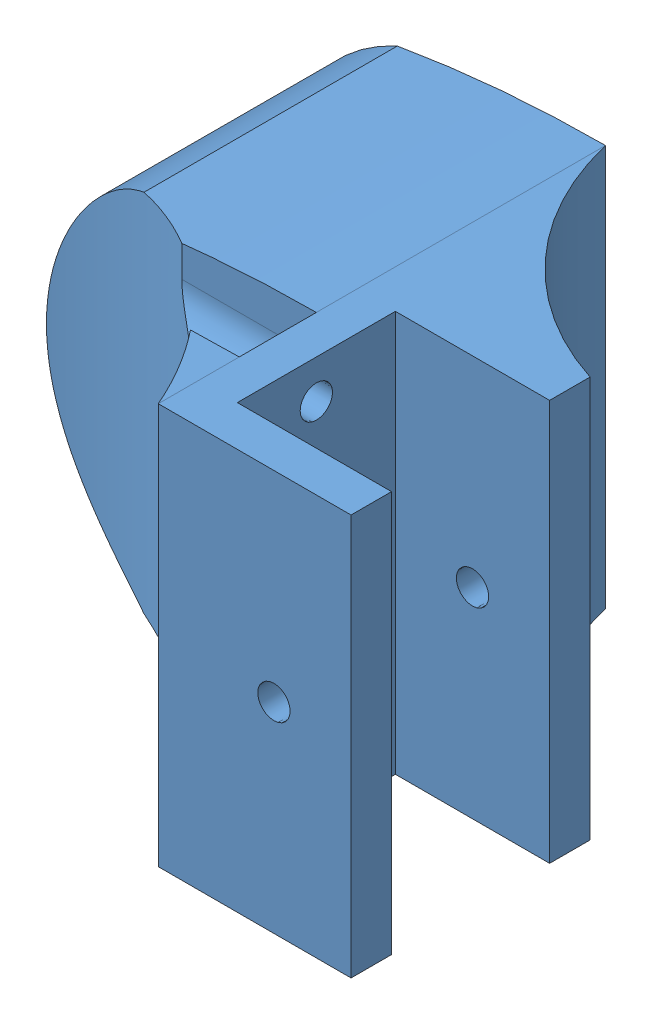
SolidWorks assembly Ролик с креплением зеркально, configuration По умолчанию. Lengths in mm.
Overall size (93.13 52 97.57).
3 component instances, 3 part files, 9 mates.
Components (placement in the parent):
- Крепление ролика зеркально-1: Крепление ролика зеркально [По умолчанию] at (0 26 -15.5) size (93.13 52 92.27)
- Шпилька-1: Шпилька [По умолчанию] at (-41.25 26 -47.8005) size (5 5 40)
- Ролик-1: Ролик [По умолчанию] at (-41.25 26 -32.05) x (1 0 0) z (0 -1 0) size (18 9 18)
Mates (geometry in assembly coordinates):
- Совпадение1: coincident anti-aligned: plane of Крепление ролика зеркально-1 through (0 0 15.5) normal (0 -1 0); plane of assembly through (0 0 0) normal (0 1 0)
- Совпадение2: coincident aligned: plane of Крепление ролика зеркально-1 through (0 26 0) normal (0 0 1); plane of assembly through (0 0 0) normal (0 0 1)
- Совпадение3: coincident aligned: plane of Крепление ролика зеркально-1 through (0 52 15.5) normal (1 0 0); plane of assembly through (0 0 0) normal (1 0 0)
- Концентричный1: concentric anti-aligned: cylinder of Крепление ролика зеркально-1 through (-41.25 26 -42.5) axis (0 0 1) radius 2.5; cylinder of Шпилька-1 through (-41.25 26 -7.8005) axis (0 0 -1) radius 2.5
- Параллельность1: parallel aligned: plane of Крепление ролика зеркально-1 through (0 52 15.5) normal (0 1 0); plane of Шпилька-1 through (-41.25 26 -47.8005) normal (0 1 0)
- Концентричный2: concentric anti-aligned: cylinder of Шпилька-1 through (-41.25 26 -7.8005) axis (0 0 -1) radius 2.5; cylinder of Ролик-1 through (-41.25 26 -23.05) axis (0 0 1) radius 2.5
- Совпадение5: coincident: line of Крепление ролика зеркально-1 through (35.2 52 -31.25) axis (1 0 0); plane of Ролик-1 through (-50.25 26 -31.25) normal (0 0 1)
- Параллельность2: parallel aligned: plane of Крепление ролика зеркально-1 through (0 52 15.5) normal (1 0 0); plane of Ролик-1
- Совпадение6: coincident aligned: plane of Крепление ролика зеркально-1 through (-41.25 26 -7.8005) normal (0 0 1); plane of Шпилька-1 through (-41.25 26 -7.8005) normal (0 0 1)
